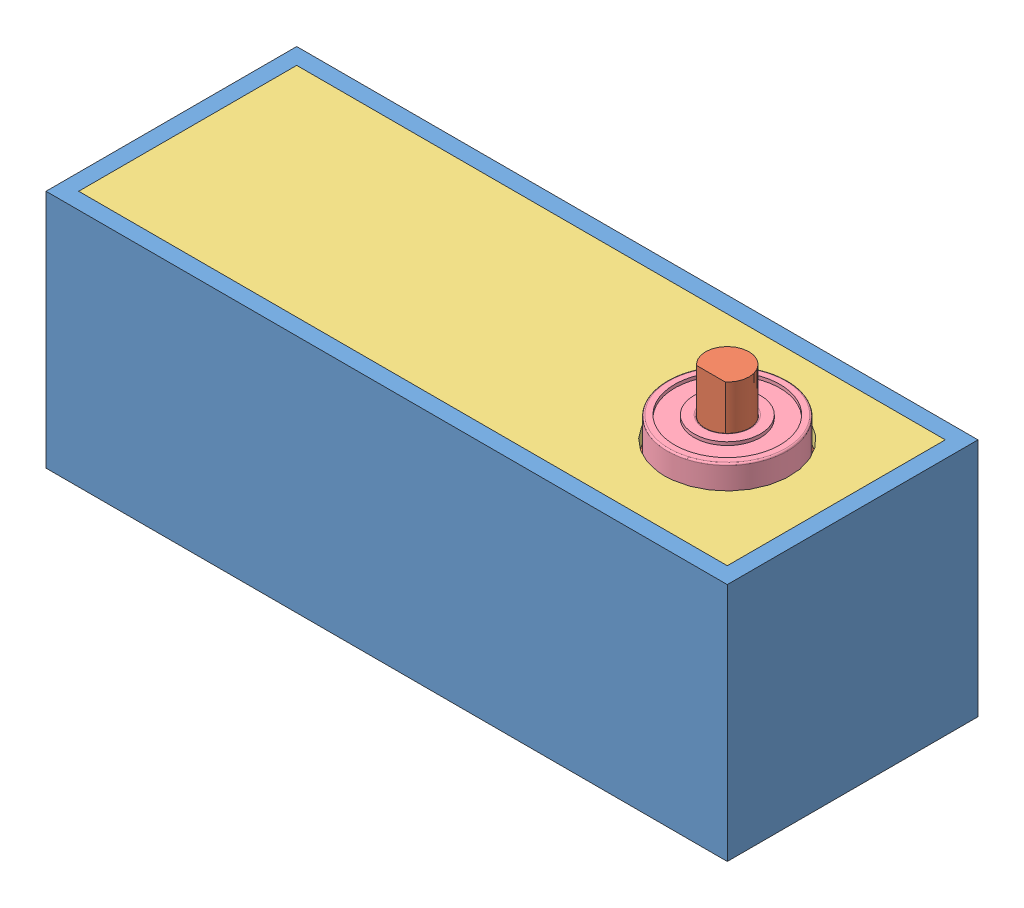
SolidWorks assembly Case2WithBearings, configuration Default. Lengths in mm.
Overall size (125 68 46).
6 component instances, 4 part files, 5 mates.
Components (placement in the parent):
- Motor2WithCase-1: Motor2WithCase [Default] at origin size (125 68 46) (flexible)
  - ArmBase2-1: ArmBase2 [Default] at origin size (125 56 46)
  - WormGearMotor-3: WormGearMotor [Default] at (-57.7 19.5 0) x (0 0 -1) z (0 -1 0) size (40 117.2 52)
  - ArmBaseCover-3: ArmBaseCover [Default] at (0 44 0) x (-1 0 0) z (0 0 1) size (119 4.5 40)
- SB608ZZ-1: SB608ZZ [Default] at (39.5 48 0) x (0 -1 0) z (0.818908 0 -0.573924) size (7 22 22)
- SB608ZZ-2: SB608ZZ [Default] at (39.5 3 0) x (0 -1 0) z (0 0 1) size (7 22 22)
Mates (geometry in assembly coordinates):
- Concentric1: concentric anti-aligned: cylinder of Motor2WithCase-1/WormGearMotor-3 through (39.5 36 0) axis (0 1 0) radius 4; cylinder of SB608ZZ-1 through (39.5 41.3 0) axis (0 -1 0) radius 4
- Coincident1: coincident anti-aligned: plane of Motor2WithCase-1/WormGearMotor-3 through (39.5 41 0) normal (0 1 0); plane of SB608ZZ-1 through (33.9616 41 -7.9025) normal (0 -1 0)
- Concentric2: concentric anti-aligned: cylinder of Motor2WithCase-1/ArmBase2-1 through (39.5 -12 0) axis (0 1 0) radius 4; cylinder of SB608ZZ-2 through (39.5 -3.7 0) axis (0 -1 0) radius 4
- Coincident2: coincident anti-aligned: plane of Motor2WithCase-1/ArmBase2-1 through (39.5 3 0) normal (0 -1 0); plane of SB608ZZ-2 through (50.2 3 0) normal (0 1 0)
- Coincident3: coordinate: point of Motor2WithCase-1
